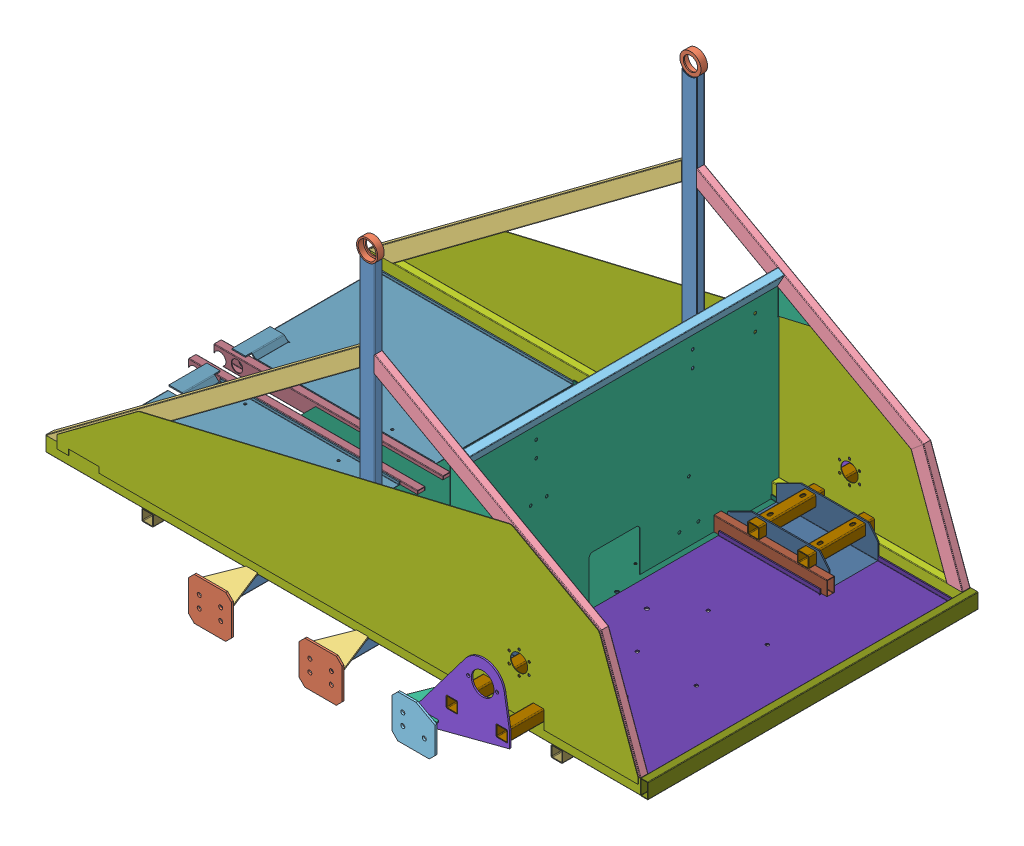
SolidWorks assembly ТП.016.01.01.00 - Корпус, configuration 00. Lengths in mm.
Overall size (1585 989.69 1098).
87 component instances, 26 part files, 22 mates.
Components (placement in the parent):
- ТП.016.01.01.01.00 - Рама корпуса-1: ТП.016.01.01.01.00 - Рама корпуса [00] at origin size (1585 284.02 1098)
  - ТП.016.01.01.01.01.00 - Поперечная балка в сборе-1: ТП.016.01.01.01.01.00 - Поперечная балка в сборе [Центральная] at (824.8534 -30 544) size (112 110.77 1078)
    - ТП.016.01.01.01.01.01 - Поперечная балка (30х30)-1: ТП.016.01.01.01.01.01 - Поперечная балка (30х30) [--] at origin size (30 30 1068)
    - ТП.016.01.01.01.01.02 - Пластина кронштейна (5мм)-1: ТП.016.01.01.01.01.02 - Пластина кронштейна (5мм) [--] at (0 -56.7738 -5) size (112 110.77 5)
    - ТП.016.01.01.01.01.03 - Косынка верхняя (4мм)-1: ТП.016.01.01.01.01.03 - Косынка верхняя (4мм) [--] at (0 30 -10) size (112 4 104)
    - ТП.016.01.01.01.01.02 - Пластина кронштейна (5мм)-2: ТП.016.01.01.01.01.02 - Пластина кронштейна (5мм) [--] at (0 -56.7738 -1083) x (-1 0 0) z (0 0 -1) size (112 110.77 5)
    - ТП.016.01.01.01.01.03 - Косынка верхняя (4мм)-2: ТП.016.01.01.01.01.03 - Косынка верхняя (4мм) [--] at (0 30 -1078) x (-1 0 0) z (0 0 -1) size (112 4 104)
    - ТП.016.01.01.01.01.04 - Косынка нижняя (4мм)-2: ТП.016.01.01.01.01.04 - Косынка нижняя (4мм) [--] at (0 0 -1078) x (-1 0 0) z (0 0 -1) size (4 53.77 53.77)
    - ТП.016.01.01.01.01.04 - Косынка нижняя (4мм)-3: ТП.016.01.01.01.01.04 - Косынка нижняя (4мм) [--] at (0 0 -10) size (4 53.77 53.77)
    - ТП.016.01.01.01.01.05 - Пластина кронштейна задняя (5мм)-1: ТП.016.01.01.01.01.05 - Пластина кронштейна задняя (5мм) [--] at (0 -56.7738 -1083) x (-1 0 0) z (0 0 -1) size (112 110.77 5) (hidden)
    - ТП.016.01.01.01.01.06 - Косынка верхняя задняя (4мм)-1: ТП.016.01.01.01.01.06 - Косынка верхняя задняя (4мм) [--] at (-15 30 -1078) x (-1 0 0) z (0 0 -1) size (111.99 4 104) (hidden)
    - ТП.016.01.01.01.01.05 - Пластина кронштейна задняя (5мм)-2: ТП.016.01.01.01.01.05 - Пластина кронштейна задняя (5мм) [--] at (0 -56.7738 -10) x (-1 0 0) z (0 0 -1) size (112 110.77 5) (hidden)
    - ТП.016.01.01.01.01.06 - Косынка верхняя задняя (4мм)-2: ТП.016.01.01.01.01.06 - Косынка верхняя задняя (4мм) [--] at (-15 34 -10) x (-1 0 0) z (0 0 1) size (111.99 4 104) (hidden)
  - ТП.016.01.01.01.01.00 - Поперечная балка в сборе-2: ТП.016.01.01.01.01.00 - Поперечная балка в сборе [Центральная] at (536.5267 -30 544) size (112 110.77 1078)
    - ТП.016.01.01.01.01.01 - Поперечная балка (30х30)-1: ТП.016.01.01.01.01.01 - Поперечная балка (30х30) [--] at origin size (30 30 1068)
    - ТП.016.01.01.01.01.02 - Пластина кронштейна (5мм)-1: ТП.016.01.01.01.01.02 - Пластина кронштейна (5мм) [--] at (0 -56.7738 -5) size (112 110.77 5)
    - ТП.016.01.01.01.01.03 - Косынка верхняя (4мм)-1: ТП.016.01.01.01.01.03 - Косынка верхняя (4мм) [--] at (0 30 -10) size (112 4 104)
    - ТП.016.01.01.01.01.02 - Пластина кронштейна (5мм)-2: ТП.016.01.01.01.01.02 - Пластина кронштейна (5мм) [--] at (0 -56.7738 -1083) x (-1 0 0) z (0 0 -1) size (112 110.77 5)
    - ТП.016.01.01.01.01.03 - Косынка верхняя (4мм)-2: ТП.016.01.01.01.01.03 - Косынка верхняя (4мм) [--] at (0 30 -1078) x (-1 0 0) z (0 0 -1) size (112 4 104)
    - ТП.016.01.01.01.01.04 - Косынка нижняя (4мм)-2: ТП.016.01.01.01.01.04 - Косынка нижняя (4мм) [--] at (0 0 -1078) x (-1 0 0) z (0 0 -1) size (4 53.77 53.77)
    - ТП.016.01.01.01.01.04 - Косынка нижняя (4мм)-3: ТП.016.01.01.01.01.04 - Косынка нижняя (4мм) [--] at (0 0 -10) size (4 53.77 53.77)
    - ТП.016.01.01.01.01.05 - Пластина кронштейна задняя (5мм)-1: ТП.016.01.01.01.01.05 - Пластина кронштейна задняя (5мм) [--] at (0 -56.7738 -1083) x (-1 0 0) z (0 0 -1) size (112 110.77 5) (hidden)
    - ТП.016.01.01.01.01.06 - Косынка верхняя задняя (4мм)-1: ТП.016.01.01.01.01.06 - Косынка верхняя задняя (4мм) [--] at (-15 30 -1078) x (-1 0 0) z (0 0 -1) size (111.99 4 104) (hidden)
    - ТП.016.01.01.01.01.05 - Пластина кронштейна задняя (5мм)-2: ТП.016.01.01.01.01.05 - Пластина кронштейна задняя (5мм) [--] at (0 -56.7738 -10) x (-1 0 0) z (0 0 -1) size (112 110.77 5) (hidden)
    - ТП.016.01.01.01.01.06 - Косынка верхняя задняя (4мм)-2: ТП.016.01.01.01.01.06 - Косынка верхняя задняя (4мм) [--] at (-15 34 -10) x (-1 0 0) z (0 0 1) size (111.99 4 104) (hidden)
  - ТП.016.01.01.01.01.00 - Поперечная балка в сборе-3: ТП.016.01.01.01.01.00 - Поперечная балка в сборе [Задняя] at (1067.2668 -30 544) size (112 110.77 1078)
    - ТП.016.01.01.01.01.01 - Поперечная балка (30х30)-1: ТП.016.01.01.01.01.01 - Поперечная балка (30х30) [Под лебедку] at origin size (30 30 1068)
    - ТП.016.01.01.01.01.02 - Пластина кронштейна (5мм)-1: ТП.016.01.01.01.01.02 - Пластина кронштейна (5мм) [--] at (0 -56.7738 -5) size (112 110.77 5) (hidden)
    - ТП.016.01.01.01.01.03 - Косынка верхняя (4мм)-1: ТП.016.01.01.01.01.03 - Косынка верхняя (4мм) [--] at (0 30 -10) size (112 4 104) (hidden)
    - ТП.016.01.01.01.01.02 - Пластина кронштейна (5мм)-2: ТП.016.01.01.01.01.02 - Пластина кронштейна (5мм) [--] at (0 -56.7738 -1083) x (-1 0 0) z (0 0 -1) size (112 110.77 5) (hidden)
    - ТП.016.01.01.01.01.03 - Косынка верхняя (4мм)-2: ТП.016.01.01.01.01.03 - Косынка верхняя (4мм) [--] at (0 30 -1078) x (-1 0 0) z (0 0 -1) size (112 4 104) (hidden)
    - ТП.016.01.01.01.01.04 - Косынка нижняя (4мм)-2: ТП.016.01.01.01.01.04 - Косынка нижняя (4мм) [--] at (0 0 -1078) x (-1 0 0) z (0 0 -1) size (4 53.77 53.77)
    - ТП.016.01.01.01.01.04 - Косынка нижняя (4мм)-3: ТП.016.01.01.01.01.04 - Косынка нижняя (4мм) [--] at (0 0 -10) size (4 53.77 53.77)
    - ТП.016.01.01.01.01.05 - Пластина кронштейна задняя (5мм)-1: ТП.016.01.01.01.01.05 - Пластина кронштейна задняя (5мм) [--] at (0 -56.7738 -1083) x (-1 0 0) z (0 0 -1) size (112 110.77 5)
    - ТП.016.01.01.01.01.06 - Косынка верхняя задняя (4мм)-1: ТП.016.01.01.01.01.06 - Косынка верхняя задняя (4мм) [--] at (-15 30 -1078) x (-1 0 0) z (0 0 -1) size (111.99 4 104)
    - ТП.016.01.01.01.01.05 - Пластина кронштейна задняя (5мм)-2: ТП.016.01.01.01.01.05 - Пластина кронштейна задняя (5мм) [--] at (0 -56.7738 -10) x (-1 0 0) z (0 0 -1) size (112 110.77 5)
    - ТП.016.01.01.01.01.06 - Косынка верхняя задняя (4мм)-2: ТП.016.01.01.01.01.06 - Косынка верхняя задняя (4мм) [--] at (-15 34 -10) x (-1 0 0) z (0 0 1) size (111.99 4 104)
  - ТП.016.01.01.01.02 - Балка платформы боковая (40х20)-1: ТП.016.01.01.01.02 - Балка платформы боковая (40х20) [--] at (250 0 -420) x (0 0 -1) z (1 0 0) size (20 40 1550)
  - ТП.016.01.01.01.02 - Балка платформы боковая (40х20)-2: ТП.016.01.01.01.02 - Балка платформы боковая (40х20) [--] at (250 0 420) x (0 0 -1) z (1 0 0) size (20 40 1550)
  - Схема рамы ЭСКИЗ-1: Схема рамы ЭСКИЗ [--] x (0 0 -1) z (1 0 0) size (559 0 1052.27)
  - ТП.016.01.01.01.03.00 - Опора редуктора-1: ТП.016.01.01.01.03.00 - Опора редуктора [Правая] at (1235 143.2262 -526.5) x (-1 0 0) z (0 0 -1) size (276.73 227.25 267.34)
    - ТП.016.01.01.01.03.01 - Щека ведущей оси (4мм)-1: ТП.016.01.01.01.03.01 - Щека ведущей оси (4мм) [--] at origin size (249.73 227.25 4)
    - ТП.016.01.01.01.03.02 - Балка опоры ребуктора (30х30)-1: ТП.016.01.01.01.03.02 - Балка опоры ребуктора (30х30) [--] at (65 -72 0) size (30 30 267.34)
    - ТП.016.01.01.01.03.02 - Балка опоры ребуктора (30х30)-2: ТП.016.01.01.01.03.02 - Балка опоры ребуктора (30х30) [--] at (-65 -72 0) size (30 30 267.34)
    - ТП.016.01.01.01.03.02 - Балка опоры ребуктора (30х30)-3: ТП.016.01.01.01.03.02 - Балка опоры ребуктора (30х30) [--] at (95 -72 -4) x (-1 0 0) z (0 0 -1) size (30 30 267.34) (hidden)
    - ТП.016.01.01.01.03.02 - Балка опоры ребуктора (30х30)-4: ТП.016.01.01.01.03.02 - Балка опоры ребуктора (30х30) [--] at (-35 -72 -4) x (-1 0 0) z (0 0 -1) size (30 30 267.34) (hidden)
    - ТП.016.01.01.01.03.03 - Пол под редуктор (3мм)-1: ТП.016.01.01.01.03.03 - Пол под редуктор (3мм) [--] at (65 -143.2262 -181.9182) x (0 0 -1) z (1 0 0) size (130.84 76.23 264.73)
  - ТП.016.01.01.01.03.00 - Опора редуктора-2: ТП.016.01.01.01.03.00 - Опора редуктора [Левая] at (1235 143.2262 522.5) x (-1 0 0) z (0 0 -1) size (276.73 227.25 267.34)
    - ТП.016.01.01.01.03.01 - Щека ведущей оси (4мм)-1: ТП.016.01.01.01.03.01 - Щека ведущей оси (4мм) [--] at origin size (249.73 227.25 4)
    - ТП.016.01.01.01.03.02 - Балка опоры ребуктора (30х30)-1: ТП.016.01.01.01.03.02 - Балка опоры ребуктора (30х30) [--] at (65 -72 0) size (30 30 267.34) (hidden)
    - ТП.016.01.01.01.03.02 - Балка опоры ребуктора (30х30)-2: ТП.016.01.01.01.03.02 - Балка опоры ребуктора (30х30) [--] at (-65 -72 0) size (30 30 267.34) (hidden)
    - ТП.016.01.01.01.03.02 - Балка опоры ребуктора (30х30)-3: ТП.016.01.01.01.03.02 - Балка опоры ребуктора (30х30) [--] at (95 -72 -4) x (-1 0 0) z (0 0 -1) size (30 30 267.34)
    - ТП.016.01.01.01.03.02 - Балка опоры ребуктора (30х30)-4: ТП.016.01.01.01.03.02 - Балка опоры ребуктора (30х30) [--] at (-35 -72 -4) x (-1 0 0) z (0 0 -1) size (30 30 267.34)
    - ТП.016.01.01.01.03.03 - Пол под редуктор (3мм)-1: ТП.016.01.01.01.03.03 - Пол под редуктор (3мм) [--] at (65 -143.2262 177.9182) x (0 0 -1) z (1 0 0) size (130.84 76.23 264.73)
  - ТП.016.01.01.01.04 - Опора короткая под редуктор (40х20)-1: ТП.016.01.01.01.04 - Опора короткая под редуктор (40х20) [--] at (1052.2668 0 -259.1637) x (0 0 -1) z (1 0 0) size (20 40 294.73)
  - ТП.016.01.01.01.04 - Опора короткая под редуктор (40х20)-2: ТП.016.01.01.01.04 - Опора короткая под редуктор (40х20) [--] at (1052.2668 0 279.1637) x (0 0 -1) z (1 0 0) size (20 40 294.73)
  - ТП.016.01.01.01.05 - Поперечина короткая (30х30)-1: ТП.016.01.01.01.05 - Поперечина короткая (30х30) [--] at (1347 0 0) size (30 30 860)
  - ТП.016.01.01.01.05 - Поперечина короткая (30х30)-2: ТП.016.01.01.01.05 - Поперечина короткая (30х30) [--] at (280 0 0) size (30 30 860)
  - ТП.016.01.01.01.06 - Поддержка центральная (40х20)-1: ТП.016.01.01.01.06 - Поддержка центральная (40х20) [--] at (45 -9.1741 -23) x (0 0 1) z (-1 0 0) size (20 40 596.53)
  - ТП.016.01.01.01.06 - Поддержка центральная (40х20)-2: ТП.016.01.01.01.06 - Поддержка центральная (40х20) [--] at (45 -9.1741 43) x (0 0 1) z (-1 0 0) size (20 40 596.53)
  - ТП.016.01.01.01.07 - Пол перед (3мм)-1: ТП.016.01.01.01.07 - Пол перед (3мм) [Правый] at (0 0 -410) x (0 0 -1) z (1 0 0) size (377 29.49 517.11)
  - ТП.016.01.01.01.07 - Пол перед (3мм)-2: ТП.016.01.01.01.07 - Пол перед (3мм) [Левый] at (0 0 -344) x (0 0 -1) z (1 0 0) size (754 29.49 517.11)
  - ТП.016.01.01.01.08 - Пол центр (2мм)-1: ТП.016.01.01.01.08 - Пол центр (2мм) [--] at (250 0 0) x (0 0 -1) z (1 0 0) size (820 12 817.27)
  - ТП.016.01.01.01.09 - Задний бампер (40х20)-1: ТП.016.01.01.01.09 - Задний бампер (40х20) [--] at (1570 0 0) size (20 40 860)
  - ТП.016.01.01.01.10 - Пол капота (3мм)-1: ТП.016.01.01.01.10 - Пол капота (3мм) [--] at (1550 0 0) x (0 0 1) z (-1 0 0) size (820 13 482.73)
  - Гайка (ГОСТ ISO 4032-2014)-1: Гайка (ГОСТ ISO 4032-2014) [Гайка М6 (ГОСТ ISO 4032)] at (153.1386 -2.6 64.0253) x (-0.998033 0 -0.062689) z (0 1 0) size (10 11.05 5.2)
  - Гайка (ГОСТ ISO 4032-2014)-2: Гайка (ГОСТ ISO 4032-2014) [Гайка М6 (ГОСТ ISO 4032)] at (403.0634 -2.6 70.156) x (-0.991964 0 0.126519) z (0 1 0) size (10 11.05 5.2)
  - Гайка (ГОСТ ISO 4032-2014)-3: Гайка (ГОСТ ISO 4032-2014) [Гайка М6 (ГОСТ ISO 4032)] at (672.9822 -2.6 76.7772) x (-0.941367 0 0.337385) z (0 1 0) size (10 11.05 5.2)
  - Гайка (ГОСТ ISO 4032-2014)-4: Гайка (ГОСТ ISO 4032-2014) [Гайка М6 (ГОСТ ISO 4032)] at (1021.6211 -2.6 85.3294) x (-0.83604 0 0.548669) z (0 1 0) size (10 11.05 5.2)
  - Гайка (ГОСТ ISO 4032-2014)-5: Гайка (ГОСТ ISO 4032-2014) [Гайка М6 (ГОСТ ISO 4032)] at (1021.6211 -2.6 -85.3294) x (-0.680834 0 0.732437) z (0 1 0) size (10 11.05 5.2)
  - Гайка (ГОСТ ISO 4032-2014)-6: Гайка (ГОСТ ISO 4032-2014) [Гайка М6 (ГОСТ ISO 4032)] at (672.9822 -2.6 -76.7772) x (-0.498939 0 0.866637) z (0 1 0) size (10 11.05 5.2)
  - Гайка (ГОСТ ISO 4032-2014)-7: Гайка (ГОСТ ISO 4032-2014) [Гайка М6 (ГОСТ ISO 4032)] at (403.0634 -2.6 -70.156) x (-0.323185 0 0.946336) z (0 1 0) size (10 11.05 5.2)
  - Гайка (ГОСТ ISO 4032-2014)-8: Гайка (ГОСТ ISO 4032-2014) [Гайка М6 (ГОСТ ISO 4032)] at (153.1386 -2.6 -64.0253) x (-0.182176 0 0.983266) z (0 1 0) size (10 11.05 5.2)
- ТП.016.01.01.02.00 - Вертикальная опора рычага-1: ТП.016.01.01.02.00 - Вертикальная опора рычага [00] at (837.2668 40 -410) x (0 0 -1) z (1 0 0) size (20 865.92 61.84)
  - ТП.016.01.01.02.01 - Вертикальная поддержка оси защиты (40х20)-1: ТП.016.01.01.02.01 - Вертикальная поддержка оси защиты (40х20) [--] at origin size (20 816.26 40)
  - ТП.016.01.01.02.02 - Обойма оси рычага-1: ТП.016.01.01.02.02 - Обойма оси рычага [--] at (20 835 0) x (1 0 0) z (0 -0.133324 -0.991073) size (17 55 55)
- ТП.016.01.01.03 - Фронтальная наклонная поддержка (40х20)-1: ТП.016.01.01.03 - Фронтальная наклонная поддержка (40х20) [--] at (817.2668 40 -428.5) x (-1 0 0) z (0 0 -1) size (842.66 642.08 20)
- ТП.016.01.01.04 - Задняя наклонная поддержка (40х20)-1: ТП.016.01.01.04 - Задняя наклонная поддержка (40х20) [--] at (857.2668 40 -428.5) x (-1 0 0) z (0 0 -1) size (694.23 610.67 20)
- ТП.016.01.01.04 - Задняя наклонная поддержка (40х20)-2: ТП.016.01.01.04 - Задняя наклонная поддержка (40х20) [--] at (857.2668 40 411.5) x (-1 0 0) z (0 0 -1) size (694.23 610.67 20)
- ТП.016.01.01.03 - Фронтальная наклонная поддержка (40х20)-2: ТП.016.01.01.03 - Фронтальная наклонная поддержка (40х20) [--] at (817.2668 40 411.5) x (-1 0 0) z (0 0 -1) size (842.66 642.08 20)
- ТП.016.01.01.02.00 - Вертикальная опора рычага-2: ТП.016.01.01.02.00 - Вертикальная опора рычага [00] at (837.2668 40 410) x (0 0 1) z (-1 0 0) size (20 865.92 61.84)
  - ТП.016.01.01.02.01 - Вертикальная поддержка оси защиты (40х20)-1: ТП.016.01.01.02.01 - Вертикальная поддержка оси защиты (40х20) [--] at origin size (20 816.26 40)
  - ТП.016.01.01.02.02 - Обойма оси рычага-1: ТП.016.01.01.02.02 - Обойма оси рычага [--] at (20 835 0) x (1 0 0) z (0 -0.133324 -0.991073) size (17 55 55)
- ТП.016.01.01.05 - Поперечина между бортами верхняя (40х20)-1: ТП.016.01.01.05 - Поперечина между бортами верхняя (40х20) [--] at (1098.7044 515.2767 410) x (0.874527 -0.484977 0) z (0 0 1) size (20 40 820)
- ТП.016.01.01.06 - Стенка моторного отсека (1_5мм)-1: ТП.016.01.01.06 - Стенка моторного отсека (1_5мм) [--] at (1052.2668 0 0) x (0 0 -1) z (1 0 0) size (857 493.29 116.33)
- ТП.016.01.01.07 - Бок корпуса (1_5мм)-2: ТП.016.01.01.07 - Бок корпуса (1_5мм) [--] at (817.2668 40 -430) x (-1 0 0) z (0 0 -1) size (1514.68 420.65 1.5)
- ТП.016.01.01.07 - Бок корпуса (1_5мм)-3: ТП.016.01.01.07 - Бок корпуса (1_5мм) [--] at (817.2668 40 431.5) x (-1 0 0) z (0 0 -1) size (1514.68 420.65 1.5)
Mates (geometry in assembly coordinates):
- Совпадение1: coincident: plane of ТП.016.01.01.01.00 - Рама корпуса-1/ТП.016.01.01.01.02 - Балка платформы боковая (40х20)-1 through (0 38.5 -430) normal (0 0 -1); plane of ТП.016.01.01.07 - Бок корпуса (1_5мм)-2 through (1143 68.2262 -430) normal (0 0 1)
- Совпадение2: coincident: plane of ТП.016.01.01.01.00 - Рама корпуса-1/ТП.016.01.01.01.03.00 - Опора редуктора-1/ТП.016.01.01.01.03.02 - Балка опоры ребуктора (30х30)-2 through (1297 71.2262 -181.7373) normal (0 1 0); plane of ТП.016.01.01.07 - Бок корпуса (1_5мм)-2 through (1143 71.2262 -431.5) normal (0 -1 0)
- Совпадение3: coincident: plane of ТП.016.01.01.01.00 - Рама корпуса-1/ТП.016.01.01.01.03.00 - Опора редуктора-1/ТП.016.01.01.01.03.02 - Балка опоры ребуктора (30х30)-1 through (1140 68.2262 -181.7373) normal (-1 0 0); plane of ТП.016.01.01.07 - Бок корпуса (1_5мм)-2 through (1140 23.5 -431.5) normal (1 0 0)
- Совпадение4: coincident: plane of ТП.016.01.01.01.00 - Рама корпуса-1/ТП.016.01.01.01.02 - Балка платформы боковая (40х20)-1 through (0 40 -411.5) normal (0 1 0); plane of ТП.016.01.01.02.00 - Вертикальная опора рычага-1/ТП.016.01.01.02.01 - Вертикальная поддержка оси защиты (40х20)-1 through (855.7668 40 -411.5) normal (0 -1 0)
- Совпадение5: coincident: plane of ТП.016.01.01.01.00 - Рама корпуса-1/ТП.016.01.01.01.02 - Балка платформы боковая (40х20)-1 through (0 38.5 -410) normal (0 0 1); plane of ТП.016.01.01.02.00 - Вертикальная опора рычага-1/ТП.016.01.01.02.01 - Вертикальная поддержка оси защиты (40х20)-1 through (855.7668 902.501 -410) normal (0 0 1)
- Совпадение6: coincident: plane of ТП.016.01.01.02.00 - Вертикальная опора рычага-1/ТП.016.01.01.02.01 - Вертикальная поддержка оси защиты (40х20)-1 through (817.2668 902.501 -428.5) normal (-1 0 0); plane of ТП.016.01.01.03 - Фронтальная наклонная поддержка (40х20)-1 through (817.2668 902.501 -411.5) normal (1 0 0)
- Совпадение7: coincident: plane of ТП.016.01.01.01.00 - Рама корпуса-1/ТП.016.01.01.01.02 - Балка платформы боковая (40х20)-1 through (0 40 -411.5) normal (0 1 0); plane of ТП.016.01.01.03 - Фронтальная наклонная поддержка (40х20)-1 through (1550 40 -428.5) normal (0 -1 0)
- Совпадение8: coincident: plane of ТП.016.01.01.01.00 - Рама корпуса-1/ТП.016.01.01.01.02 - Балка платформы боковая (40х20)-1 through (0 38.5 -430) normal (0 0 -1); plane of ТП.016.01.01.03 - Фронтальная наклонная поддержка (40х20)-1 through (846.5061 668.7959 -430) normal (0 0 -1)
- Совпадение9: coincident: line of ТП.016.01.01.01.00 - Рама корпуса-1/ТП.016.01.01.01.02 - Балка платформы боковая (40х20)-1 through (0 40 -428.5) axis (0 0 1); line of ТП.016.01.01.03 - Фронтальная наклонная поддержка (40х20)-1 through (0 40 -411.5) axis (0 0 -1)
- Совпадение10: coincident: plane of ТП.016.01.01.01.00 - Рама корпуса-1/ТП.016.01.01.01.02 - Балка платформы боковая (40х20)-1 through (0 40 -411.5) normal (0 1 0); plane of ТП.016.01.01.04 - Задняя наклонная поддержка (40х20)-1 through (1550 40 -428.5) normal (0 -1 0)
- Совпадение11: coincident: plane of ТП.016.01.01.02.00 - Вертикальная опора рычага-1/ТП.016.01.01.02.01 - Вертикальная поддержка оси защиты (40х20)-1 through (857.2668 902.501 -428.5) normal (1 0 0); plane of ТП.016.01.01.04 - Задняя наклонная поддержка (40х20)-1 through (857.2668 902.501 -411.5) normal (-1 0 0)
- Совпадение12: coincident: plane of ТП.016.01.01.01.00 - Рама корпуса-1/ТП.016.01.01.01.02 - Балка платформы боковая (40х20)-1 through (0 38.5 -430) normal (0 0 -1); plane of ТП.016.01.01.04 - Задняя наклонная поддержка (40х20)-1 through (1513.8218 26.8322 -430) normal (0 0 -1)
- Совпадение13: coincident: plane of ТП.016.01.01.04 - Задняя наклонная поддержка (40х20)-2 through (1447.394 321.9078 428.5) normal (0.484977 0.874527 0); plane of ТП.016.01.01.05 - Поперечина между бортами верхняя (40х20)-1 through (1084.3054 523.2619 -44.7214) normal (0.484977 0.874527 0)
- Совпадение14: coincident: plane of ТП.016.01.01.03 - Фронтальная наклонная поддержка (40х20)-2 through (846.5061 668.7959 410) normal (0 0 -1); plane of ТП.016.01.01.05 - Поперечина между бортами верхняя (40х20)-1 through (1050.7668 497.8372 410) normal (0 0 1)
- Расстояние1: distance = 192 mm: plane of ТП.016.01.01.02.00 - Вертикальная опора рычага-2/ТП.016.01.01.02.01 - Вертикальная поддержка оси защиты (40х20)-1 through (857.2668 902.501 428.5) normal (1 0 0); cylinder of ТП.016.01.01.05 - Поперечина между бортами верхняя (40х20)-1 through (1050.7668 497.8372 -44.7214) axis (0 0 1) radius 1.5
- Совпадение15: coincident: plane of ТП.016.01.01.05 - Поперечина между бортами верхняя (40х20)-1 through (1064.9063 488.2808 -44.7214) normal (-0.484977 -0.874527 0); line of ТП.016.01.01.06 - Стенка моторного отсека (1_5мм)-1 through (1052.2668 495.2901 -426.26) axis (0 0 1)
- Совпадение16: coincident: plane of ТП.016.01.01.01.00 - Рама корпуса-1/ТП.016.01.01.01.08 - Пол центр (2мм)-1 through (250 2 0) normal (0 1 0); line of ТП.016.01.01.06 - Стенка моторного отсека (1_5мм)-1 through (1050.7668 2 -66.5) axis (0 0 -1)
- Перпендикулярность1: perpendicular: plane of ТП.016.01.01.01.00 - Рама корпуса-1/ТП.016.01.01.01.08 - Пол центр (2мм)-1 through (250 2 0) normal (0 1 0); plane of ТП.016.01.01.06 - Стенка моторного отсека (1_5мм)-1 through (1050.7668 105 -56.5) normal (-1 0 0)
- Совпадение17: coincident: plane of ТП.016.01.01.01.00 - Рама корпуса-1/ТП.016.01.01.01.02 - Балка платформы боковая (40х20)-1 through (0 38.5 -410) normal (0 0 1); plane of ТП.016.01.01.06 - Стенка моторного отсека (1_5мм)-1 through (1050.7668 2 -410) normal (0 0 -1)
- Совпадение18: coincident: plane of ТП.016.01.01.04 - Задняя наклонная поддержка (40х20)-1 through (1428.7223 288.2385 -430) normal (0 0 -1); plane of ТП.016.01.01.07 - Бок корпуса (1_5мм)-2 through (1143 68.2262 -430) normal (0 0 1)
- Совпадение19: coincident: plane of ТП.016.01.01.01.00 - Рама корпуса-1/ТП.016.01.01.01.03.00 - Опора редуктора-1/ТП.016.01.01.01.03.02 - Балка опоры ребуктора (30х30)-1 through (1167 71.2262 -181.7373) normal (0 1 0); plane of ТП.016.01.01.07 - Бок корпуса (1_5мм)-2 through (1273 71.2262 -431.5) normal (0 -1 0)
- Совпадение20: coincident: plane of ТП.016.01.01.01.00 - Рама корпуса-1/ТП.016.01.01.01.03.00 - Опора редуктора-1/ТП.016.01.01.01.03.02 - Балка опоры ребуктора (30х30)-2 through (1270 68.2262 -181.7373) normal (-1 0 0); plane of ТП.016.01.01.07 - Бок корпуса (1_5мм)-2 through (1270 23.5 -431.5) normal (1 0 0)
